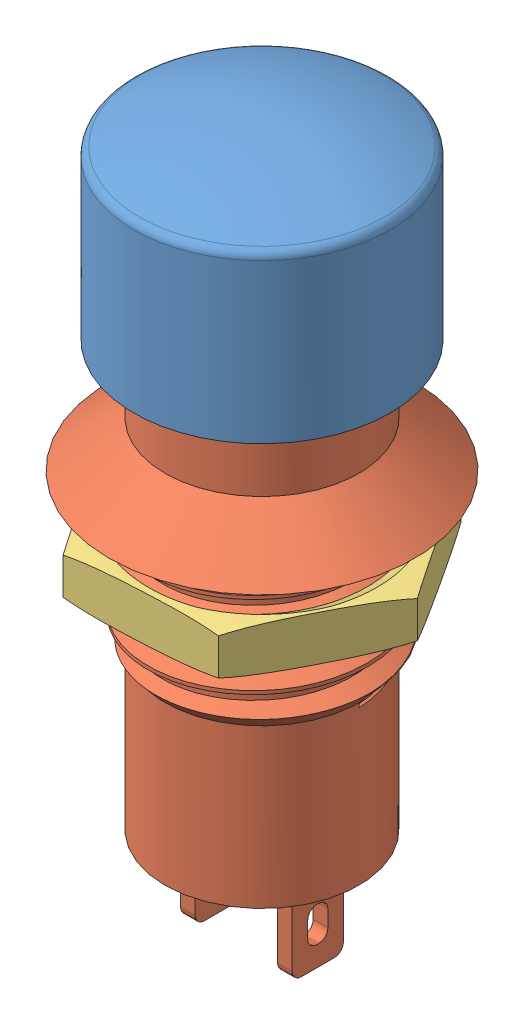
SolidWorks assembly TRU Components 1587709, configuration Default. Lengths in mm.
Overall size (20.54 38.7 21.18).
3 component instances, 3 part files, 4 mates.
Components (placement in the parent):
- PushBottom_2-1: PushBottom_2 [Default] at (10.7416 7.3599 21.2812) x (-0.98077 0 0.195166) z (-0.195166 0 -0.98077) size (14 10.5 14)
- PushBotton-1: PushBotton [Default] at (10.7416 -15.8401 21.2812) size (16.7 29.5 16.7)
- PushBottom_Screw-1: PushBottom_Screw [Default] at (10.7416 -3.3401 21.2812) x (-0.544892 0 -0.838506) z (0.838506 0 -0.544892) size (16.16 5.04 13.99)
Mates (geometry in assembly coordinates):
- Concentric1: concentric aligned: cylinder of PushBottom_2-1 through (10.7416 7.3599 21.2812) axis (0 -1 0) radius 7; cylinder of PushBotton-1 through (10.7416 -15.8401 21.2812) axis (0 -1 0) radius 5.3
- LimitDistance1: limit distance = 6.2 mm aligned: plane of PushBottom_2-1 through (10.7416 7.3599 21.2812) normal (0 -1 0); plane of PushBotton-1 through (10.7416 1.1599 21.2812) normal (0 -1 0)
- Concentric2: concentric aligned: cylinder of PushBotton-1 through (10.7416 -15.8401 21.2812) axis (0 -1 0) radius 5.3; circle of PushBottom_Screw-1
- Distance2: distance = 2 mm anti-aligned: plane of PushBotton-1 through (10.7416 1.1599 21.2812) normal (0 -1 0); plane of PushBottom_Screw-1 through (7.4722 -0.8401 16.2501) normal (0 1 0)
